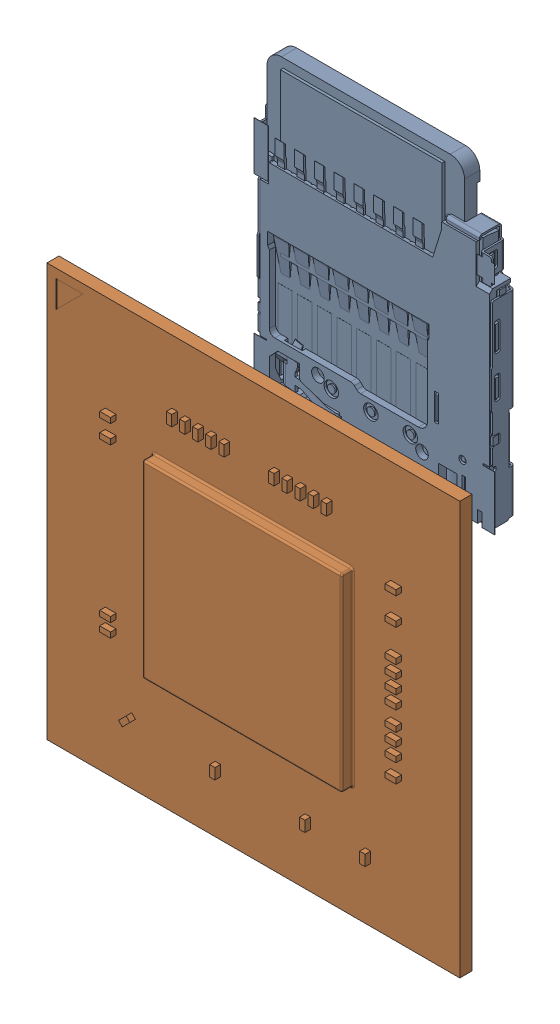
SolidWorks assembly 142-13448-1000-A02_ASM.step, configuration Default. Lengths in mm.
Overall size (23 37.01 4.01).
2 component instances, 2 part files, 0 mates.
Components (placement in the parent):
- 080-0051-000_3.step-1: 080-0051-000_3.step [Default] at (28.331 29.139 0) x (-1 0 0) z (0 0 -1) size (13.4 17 1.28)
- TM670M-A2_1.step-1: TM670M-A2_1.step [Default] at (23.7 13.45 1.2) size (23 23 1.29)
